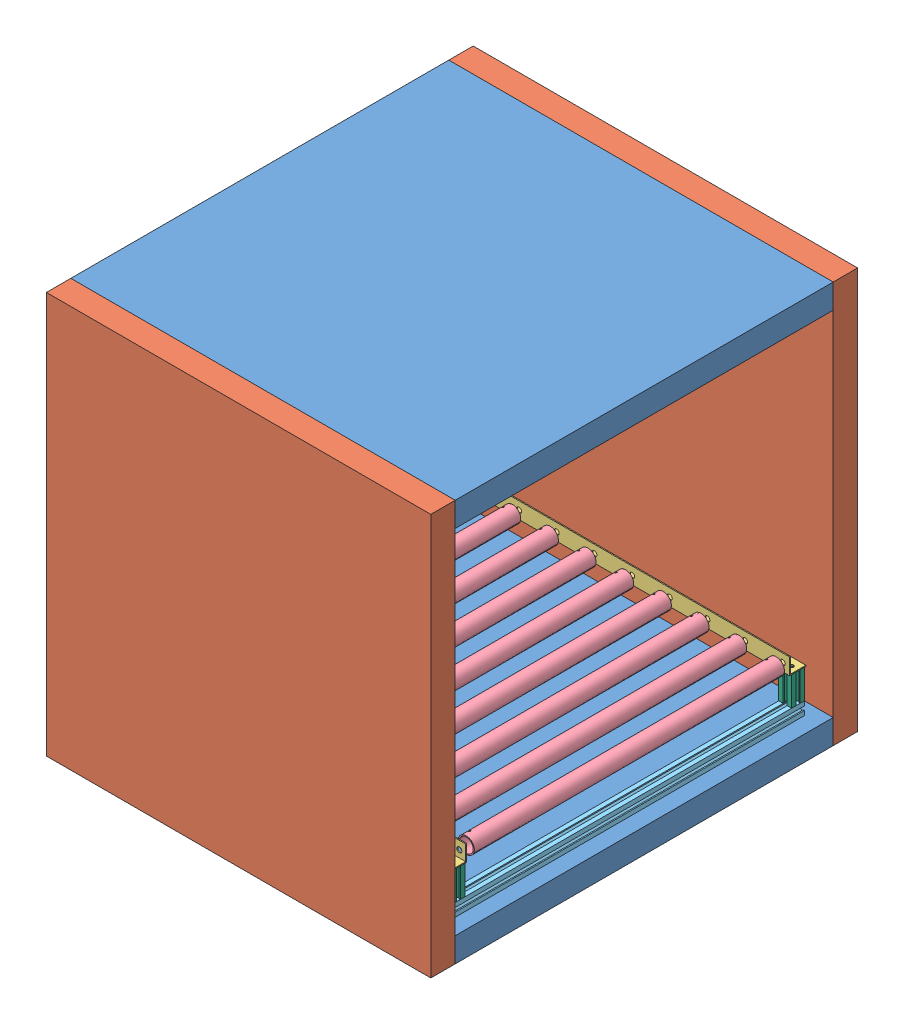
SolidWorks assembly enclosure-extension, configuration Default. Lengths in mm.
Overall size (600 626.71 666.2).
22 component instances, 6 part files, 55 mates.
Components (placement in the parent):
- horizontal-insulation-1: horizontal-insulation [Default] at (231.6745 338.5909 513.5551) size (600 38.1 590)
- vertical-insulation-1: vertical-insulation [Default] at (231.6745 651.9459 808.5551) x (1 0 0) z (0 -1 0) size (600 38.1 626.71)
- vertical-insulation-2: vertical-insulation [Default] at (231.6745 651.9459 180.4551) x (1 0 0) z (0 -1 0) size (600 38.1 626.71)
- horizontal-insulation-2: horizontal-insulation [Default] at (231.6745 927.2009 513.5551) size (600 38.1 590)
- alu-angle-1: alu-angle [Default] at (231.6745 442.0109 765.5551) x (0 0 1) z (-1 0 0) size (25.4 25.4 550)
- alu-angle-2: alu-angle [Default] at (231.6745 442.0109 261.5551) x (0 0 -1) z (1 0 0) size (25.4 25.4 550)
- alu_tube_actuated_1in-1: alu_tube_actuated_1in [Default] at (-32.5255 454.7109 513.5551) x (-0.789346 -0.613948 0) z (0 0 -1) size (25.4 25.4 484)
- alu_tube_actuated_1in-2: alu_tube_actuated_1in [Default] at (26.2745 454.7109 513.5551) x (-0.855907 -0.517129 0) z (0 0 -1) size (25.4 25.4 484)
- alu_tube_actuated_1in-3: alu_tube_actuated_1in [Default] at (84.2745 454.7109 513.5551) x (-0.923728 -0.383049 0) z (0 0 -1) size (25.4 25.4 484)
- alu_tube_actuated_1in-4: alu_tube_actuated_1in [Default] at (143.0745 454.7109 513.5551) x (-0.923728 -0.383049 0) z (0 0 -1) size (25.4 25.4 484)
- alu_tube_actuated_1in-5: alu_tube_actuated_1in [Default] at (201.8745 454.7109 513.5551) x (-0.923728 -0.383049 0) z (0 0 -1) size (25.4 25.4 484)
- alu_tube_actuated_1in-6: alu_tube_actuated_1in [Default] at (260.6745 454.7109 513.5551) x (-0.923728 -0.383049 0) z (0 0 -1) size (25.4 25.4 484)
- alu_tube_actuated_1in-7: alu_tube_actuated_1in [Default] at (319.4745 454.7109 513.5551) x (-0.923728 -0.383049 0) z (0 0 -1) size (25.4 25.4 484)
- alu_tube_actuated_1in-8: alu_tube_actuated_1in [Default] at (378.2745 454.7109 513.5551) x (-0.923728 -0.383049 0) z (0 0 -1) size (25.4 25.4 484)
- alu_tube_actuated_1in-9: alu_tube_actuated_1in [Default] at (437.0745 454.7109 513.5551) x (-0.923728 -0.383049 0) z (0 0 -1) size (25.4 25.4 484)
- alu_tube_actuated_1in-10: alu_tube_actuated_1in [Default] at (495.8745 454.7109 513.5551) x (-0.923728 -0.383049 0) z (0 0 -1) size (25.4 25.4 484)
- bottom-extrusion-1: bottom-extrusion [Default] at (-33.3255 386.6909 238.5551) size (20 20 550)
- feet-1: feet [Default] at (-33.3255 442.0109 248.5551) x (1 0 0) z (0 -1 0) size (20 20 45.32)
- feet-2: feet [Default] at (-33.3255 442.0109 778.5551) x (1 0 0) z (0 -1 0) size (20 20 45.32)
- feet-3: feet [Default] at (496.6745 442.0109 778.5551) x (1 0 0) z (0 -1 0) size (20 20 45.32)
- bottom-extrusion-2: bottom-extrusion [Default] at (496.6745 386.6909 238.5551) size (20 20 550)
- feet-4: feet [Default] at (496.6745 442.0109 248.5551) x (1 0 0) z (0 -1 0) size (20 20 45.32)
Mates (geometry in assembly coordinates):
- Coincident3: coincident aligned: plane of bottom-insulation-1 through (531.6745 376.6909 218.5551) normal (1 0 0); plane of vertical-insulation-1 through (531.6745 338.5909 846.6551) normal (1 0 0)
- Coincident4: coincident anti-aligned: plane of bottom-insulation-1 through (-68.3255 376.6909 808.5551) normal (0 0 1); plane of vertical-insulation-1 through (231.6745 651.9459 808.5551) normal (0 0 -1)
- Coincident5: coincident aligned: plane of bottom-insulation-1 through (231.6745 338.5909 513.5551) normal (0 -1 0); plane of vertical-insulation-1 through (-68.3255 338.5909 846.6551) normal (0 -1 0)
- Coincident6: coincident aligned: plane of bottom-insulation-1 through (231.6745 338.5909 513.5551) normal (0 -1 0); plane of vertical-insulation-2 through (-68.3255 338.5909 218.5551) normal (0 -1 0)
- Coincident7: coincident anti-aligned: plane of bottom-insulation-1 through (-68.3255 376.6909 218.5551) normal (0 0 -1); plane of vertical-insulation-2 through (231.6745 651.9459 218.5551) normal (0 0 1)
- Coincident8: coincident aligned: plane of bottom-insulation-1 through (531.6745 376.6909 218.5551) normal (1 0 0); plane of vertical-insulation-2 through (531.6745 338.5909 218.5551) normal (1 0 0)
- Coincident9: coincident anti-aligned: plane of vertical-insulation-1 through (231.6745 651.9459 808.5551) normal (0 0 -1); plane of horizontal-insulation-2 through (-68.3255 965.3009 808.5551) normal (0 0 1)
- Coincident10: coincident aligned: plane of vertical-insulation-2 through (531.6745 338.5909 218.5551) normal (1 0 0); plane of horizontal-insulation-2 through (531.6745 965.3009 218.5551) normal (1 0 0)
- Coincident11: coincident aligned: plane of vertical-insulation-1 through (-68.3255 965.3009 846.6551) normal (0 1 0); plane of horizontal-insulation-2 through (231.6745 965.3009 513.5551) normal (0 1 0)
- Coincident12: coincident aligned: plane of alu-angle-1 through (-43.3255 442.0109 765.5551) normal (0 -1 0); plane of alu-angle-2 through (506.6745 442.0109 261.5551) normal (0 -1 0)
- Parallel1: parallel anti-aligned: plane of horizontal-insulation-1 through (231.6745 376.6909 513.5551) normal (0 1 0); plane of alu-angle-1 through (-43.3255 442.0109 765.5551) normal (0 -1 0)
- Width1: width aligned: plane of alu-angle-1 through (-43.3255 442.0109 765.5551) normal (0 0 -1); plane of alu-angle-2 through (506.6745 442.0109 261.5551) normal (0 0 1); plane of alu_tube_actuated_1in-1 through (-32.5255 454.7109 271.5551) normal (0 0 -1); plane of alu_tube_actuated_1in-1 through (-32.5255 454.7109 755.5551) normal (0 0 1)
- Parallel2: parallel anti-aligned: plane of vertical-insulation-2 through (231.6745 651.9459 218.5551) normal (0 0 1); plane of alu-angle-1 through (-43.3255 442.0109 765.5551) normal (0 0 -1)
- Coincident14: coincident aligned: plane of alu-angle-1 through (-43.3255 442.0109 765.5551) normal (-1 0 0); plane of alu-angle-2 through (-43.3255 442.0109 261.5551) normal (-1 0 0)
- Width2: width anti-aligned: plane of vertical-insulation-2 through (231.6745 651.9459 218.5551) normal (0 0 1); plane of vertical-insulation-1 through (231.6745 651.9459 808.5551) normal (0 0 -1); plane of alu-angle-1 through (-43.3255 442.0109 765.5551) normal (0 0 -1); plane of alu-angle-2 through (506.6745 442.0109 261.5551) normal (0 0 1)
- Concentric1: concentric aligned: cylinder of alu-angle-1 through (-32.5255 454.7109 765.5551) axis (0 0 1) radius 4; cylinder of alu_tube_actuated_1in-1 through (-32.5255 454.7109 271.5551) axis (0 0 1) radius 11.049
- Concentric2: concentric aligned: cylinder of alu-angle-1 through (26.2745 454.7109 765.5551) axis (0 0 1) radius 4; cylinder of alu_tube_actuated_1in-2 through (26.2745 454.7109 271.5551) axis (0 0 1) radius 12.7
- Coincident15: coincident aligned: plane of alu_tube_actuated_1in-1 through (-32.5255 454.7109 271.5551) normal (0 0 -1); plane of alu_tube_actuated_1in-2 through (26.2745 454.7109 271.5551) normal (0 0 -1)
- Coincident16: coincident aligned: plane of alu_tube_actuated_1in-2 through (26.2745 454.7109 271.5551) normal (0 0 -1); plane of alu_tube_actuated_1in-3 through (84.2745 454.7109 271.5551) normal (0 0 -1)
- Coincident17: coincident aligned: plane of alu_tube_actuated_1in-4 through (143.0745 454.7109 271.5551) normal (0 0 -1); plane of alu_tube_actuated_1in-5 through (201.8745 454.7109 271.5551) normal (0 0 -1)
- Coincident18: coincident aligned: plane of alu_tube_actuated_1in-5 through (201.8745 454.7109 271.5551) normal (0 0 -1); plane of alu_tube_actuated_1in-6 through (260.6745 454.7109 271.5551) normal (0 0 -1)
- Coincident19: coincident aligned: plane of alu_tube_actuated_1in-3 through (84.2745 454.7109 271.5551) normal (0 0 -1); plane of alu_tube_actuated_1in-4 through (143.0745 454.7109 271.5551) normal (0 0 -1)
- Concentric3: concentric anti-aligned: cylinder of alu-angle-2 through (84.2745 454.7109 261.5551) axis (0 0 -1) radius 4; cylinder of alu_tube_actuated_1in-3 through (84.2745 454.7109 271.5551) axis (0 0 1) radius 12.7
- Concentric4: concentric anti-aligned: cylinder of alu-angle-2 through (143.0745 454.7109 261.5551) axis (0 0 -1) radius 4; cylinder of alu_tube_actuated_1in-4 through (143.0745 454.7109 271.5551) axis (0 0 1) radius 12.7
- Concentric5: concentric anti-aligned: cylinder of alu-angle-2 through (201.8745 454.7109 261.5551) axis (0 0 -1) radius 4; cylinder of alu_tube_actuated_1in-5 through (201.8745 454.7109 271.5551) axis (0 0 1) radius 12.7
- Concentric6: concentric anti-aligned: cylinder of alu-angle-2 through (260.6745 454.7109 261.5551) axis (0 0 -1) radius 4; cylinder of alu_tube_actuated_1in-6 through (260.6745 454.7109 271.5551) axis (0 0 1) radius 12.7
- Concentric7: concentric anti-aligned: cylinder of alu-angle-2 through (319.4745 454.7109 261.5551) axis (0 0 -1) radius 4; cylinder of alu_tube_actuated_1in-7 through (319.4745 454.7109 271.5551) axis (0 0 1) radius 12.7
- Coincident20: coincident aligned: plane of alu_tube_actuated_1in-6 through (260.6745 454.7109 271.5551) normal (0 0 -1); plane of alu_tube_actuated_1in-7 through (319.4745 454.7109 271.5551) normal (0 0 -1)
- Coincident21: coincident aligned: plane of alu_tube_actuated_1in-7 through (319.4745 454.7109 271.5551) normal (0 0 -1); plane of alu_tube_actuated_1in-8 through (378.2745 454.7109 271.5551) normal (0 0 -1)
- Concentric8: concentric anti-aligned: cylinder of alu-angle-2 through (378.2745 454.7109 261.5551) axis (0 0 -1) radius 4; cylinder of alu_tube_actuated_1in-8 through (378.2745 454.7109 271.5551) axis (0 0 1) radius 12.7
- Concentric9: concentric anti-aligned: cylinder of alu-angle-2 through (437.0745 454.7109 261.5551) axis (0 0 -1) radius 4; cylinder of alu_tube_actuated_1in-9 through (437.0745 454.7109 271.5551) axis (0 0 1) radius 12.7
- Coincident22: coincident aligned: plane of alu_tube_actuated_1in-8 through (378.2745 454.7109 271.5551) normal (0 0 -1); plane of alu_tube_actuated_1in-9 through (437.0745 454.7109 271.5551) normal (0 0 -1)
- Coincident23: coincident aligned: plane of alu_tube_actuated_1in-9 through (437.0745 454.7109 271.5551) normal (0 0 -1); plane of alu_tube_actuated_1in-10 through (495.8745 454.7109 271.5551) normal (0 0 -1)
- Concentric11: concentric anti-aligned: cylinder of alu-angle-2 through (495.8745 454.7109 261.5551) axis (0 0 -1) radius 4; cylinder of alu_tube_actuated_1in-10 through (495.8745 454.7109 271.5551) axis (0 0 1) radius 12.7
- Distance2: distance = 10 mm anti-aligned: plane of alu_tube_actuated_1in-1 through (-32.5255 454.7109 271.5551) normal (0 0 -1); plane of alu-angle-2 through (506.6745 442.0109 261.5551) normal (0 0 1)
- Coincident27: coincident anti-aligned: plane of horizontal-insulation-1 through (231.6745 376.6909 513.5551) normal (0 1 0); plane of bottom-extrusion-1 through (-43.3255 376.6909 788.5551) normal (0 -1 0)
- Coincident28: coincident anti-aligned: plane of bottom-extrusion-1 through (-43.3255 396.6909 788.5551) normal (0 1 0); plane of feet-1 through (-33.3255 396.6909 248.5551) normal (0 -1 0)
- Coincident29: coincident aligned: plane of bottom-extrusion-1 through (-43.3255 396.6909 788.5551) normal (-1 0 0); plane of feet-1 through (-43.3255 396.6909 245.4551) normal (-1 0 0)
- Coincident30: coincident aligned: plane of bottom-extrusion-1 through (-33.3255 386.6909 238.5551) normal (0 0 -1); plane of feet-1 through (-43.3255 396.6909 238.5551) normal (0 0 -1)
- Coincident31: coincident anti-aligned: plane of alu-angle-2 through (506.6745 442.0109 261.5551) normal (0 -1 0); plane of feet-1 through (-33.3255 442.0109 248.5551) normal (0 1 0)
- Width3: width aligned: plane of bottom-extrusion-1 through (-33.3255 386.6909 238.5551) normal (0 0 -1); plane of bottom-extrusion-1 through (-33.3255 386.6909 788.5551) normal (0 0 1); plane of vertical-insulation-1 through (231.6745 651.9459 808.5551) normal (0 0 -1); plane of vertical-insulation-2 through (231.6745 651.9459 218.5551) normal (0 0 1)
- Coincident32: coincident aligned: plane of alu-angle-2 through (-43.3255 442.0109 261.5551) normal (-1 0 0); plane of feet-1 through (-43.3255 396.6909 258.5551) normal (-1 0 0)
- Coincident33: coincident aligned: plane of bottom-extrusion-1 through (-33.3255 386.6909 788.5551) normal (0 0 1); plane of feet-2 through (-43.3255 396.6909 788.5551) normal (0 0 1)
- Coincident34: coincident aligned: plane of bottom-extrusion-1 through (-43.3255 396.6909 788.5551) normal (-1 0 0); plane of feet-2 through (-43.3255 396.6909 788.5551) normal (-1 0 0)
- Coincident35: coincident anti-aligned: plane of bottom-extrusion-1 through (-43.3255 396.6909 788.5551) normal (0 1 0); plane of feet-2 through (-33.3255 396.6909 778.5551) normal (0 -1 0)
- Distance3: distance = 25 mm aligned: plane of horizontal-insulation-1 through (-68.3255 376.6909 218.5551) normal (-1 0 0); plane of bottom-extrusion-1 through (-43.3255 383.5909 788.5551) normal (-1 0 0)
- Coincident37: coincident aligned: plane of bottom-extrusion-1 through (-33.3255 386.6909 238.5551) normal (0 0 -1); plane of bottom-extrusion-2 through (496.6745 386.6909 238.5551) normal (0 0 -1)
- Coincident38: coincident anti-aligned: plane of feet-3 through (496.6745 396.6909 778.5551) normal (0 -1 0); plane of bottom-extrusion-2 through (499.7745 396.6909 788.5551) normal (0 1 0)
- Coincident39: coincident aligned: plane of feet-3 through (506.6745 396.6909 775.4551) normal (1 0 0); plane of bottom-extrusion-2 through (506.6745 396.6909 788.5551) normal (1 0 0)
- Coincident40: coincident aligned: plane of feet-3 through (499.7745 396.6909 788.5551) normal (0 0 1); plane of bottom-extrusion-2 through (496.6745 386.6909 788.5551) normal (0 0 1)
- Coincident41: coincident aligned: plane of alu-angle-1 through (506.6745 442.0109 765.5551) normal (1 0 0); plane of feet-3 through (506.6745 396.6909 788.5551) normal (1 0 0)
- Coincident42: coincident anti-aligned: plane of horizontal-insulation-1 through (231.6745 376.6909 513.5551) normal (0 1 0); plane of bottom-extrusion-2 through (499.7745 376.6909 788.5551) normal (0 -1 0)
- Coincident43: coincident anti-aligned: plane of bottom-extrusion-2 through (499.7745 396.6909 788.5551) normal (0 1 0); plane of feet-4 through (496.6745 396.6909 248.5551) normal (0 -1 0)
- Coincident44: coincident aligned: plane of bottom-extrusion-2 through (506.6745 396.6909 788.5551) normal (1 0 0); plane of feet-4 through (506.6745 396.6909 245.4551) normal (1 0 0)
- Coincident45: coincident aligned: plane of bottom-extrusion-2 through (496.6745 386.6909 238.5551) normal (0 0 -1); plane of feet-4 through (499.7745 396.6909 238.5551) normal (0 0 -1)
